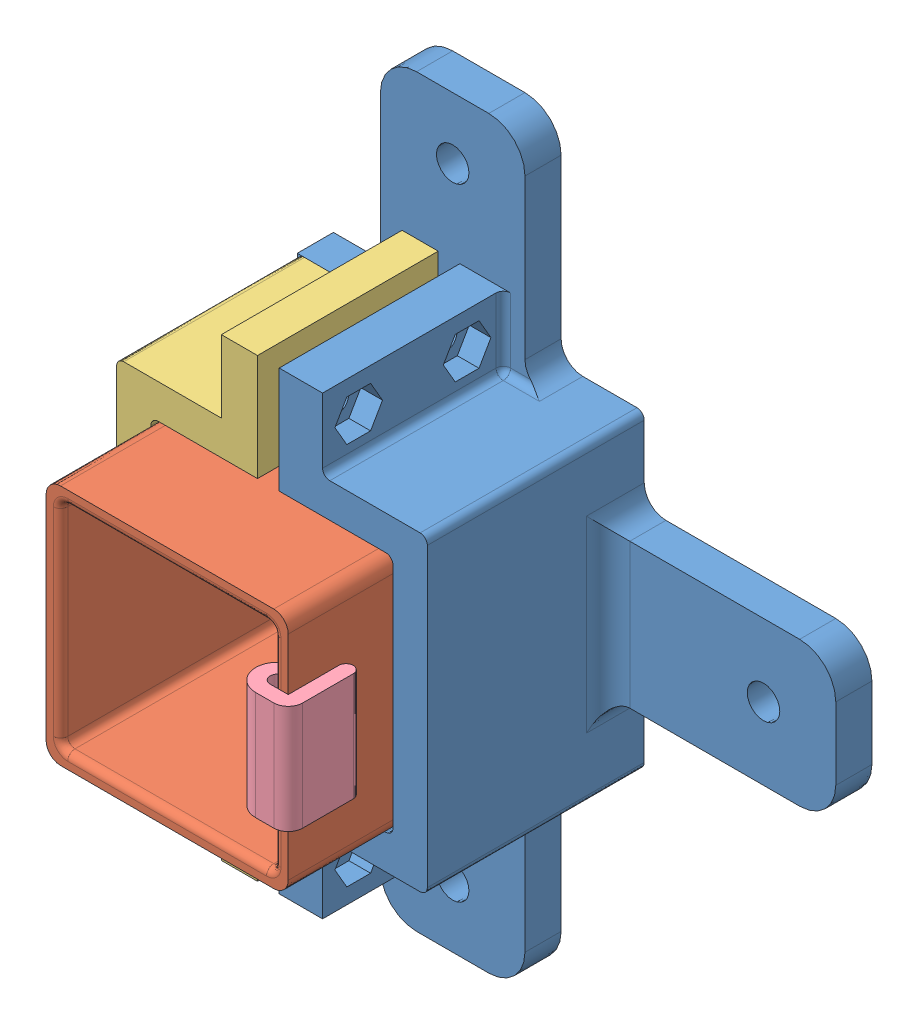
SolidWorks assembly Кювета с держателем, configuration Default. Lengths in mm.
Overall size (74.5 103 46.5).
4 component instances, 4 part files, 10 mates.
Components (placement in the parent):
- Держатель-1: Держатель [Default] at origin size (74.5 103 30)
- Квадратная кювета-1: Квадратная кювета [Default] at (-0.25 33.25 0) x (0 -1 0) z (-1 0 0) size (33.5 39.5 33.5)
- Зажим квадратный-1: Зажим квадратный [По умолчанию] at (-5 38 0) x (0 -1 0) z (-1 0 0) size (63 25 19.5)
- Клипса-1: Клипса [Default] at origin size (7.5 15 10)
Mates (geometry in assembly coordinates):
- Coincident1: coincident aligned: plane of Держатель-1 through (0 0 0) normal (0 0 1); plane of assembly through (0 0 0) normal (0 0 1)
- Coincident2: coincident aligned: plane of Держатель-1 through (0 0 0) normal (0 1 0); plane of assembly through (0 0 0) normal (0 1 0)
- Coincident3: coincident aligned: plane of Держатель-1 through (0 0 0) normal (1 0 0); plane of assembly through (0 0 0) normal (1 0 0)
- Coincident4: coincident anti-aligned: plane of Держатель-1 through (0 0 0) normal (0 0 1); plane of Квадратная кювета-1 through (-0.25 33.25 0) normal (0 0 -1)
- Совпадение1: coincident: plane of Держатель-1 through (0 16.5 0) normal (0 -1 0); line of Квадратная кювета-1 through (1.75 16.5 0) axis (1 0 0)
- Совпадение3: coincident aligned: plane of Держатель-1 through (16.5 -0.25 -37.4541) normal (0 1 0); plane of Зажим квадратный-1 through (14.5 -0.25 25) normal (0 1 0)
- Совпадение5: coincident anti-aligned: plane of Держатель-1 through (0 0 0) normal (0 0 1); plane of Зажим квадратный-1 through (-5 38 0) normal (0 0 -1)
- Совпадение6: coincident aligned: plane of Держатель-1 through (23.5 -15 25) normal (0 -1 0); plane of Зажим квадратный-1 through (9.5 -15 25) normal (0 -1 0)
- Совпадение7: coincident: plane of Зажим квадратный-1 through (14.5 -5 25) normal (1 0 0); point of assembly
- Совпадение8: coincident anti-aligned: plane of Квадратная кювета-1 through (-0.25 33.25 39.5) normal (-1 0 0); plane of Зажим квадратный-1 through (-0.25 33.25 25) normal (1 0 0)
